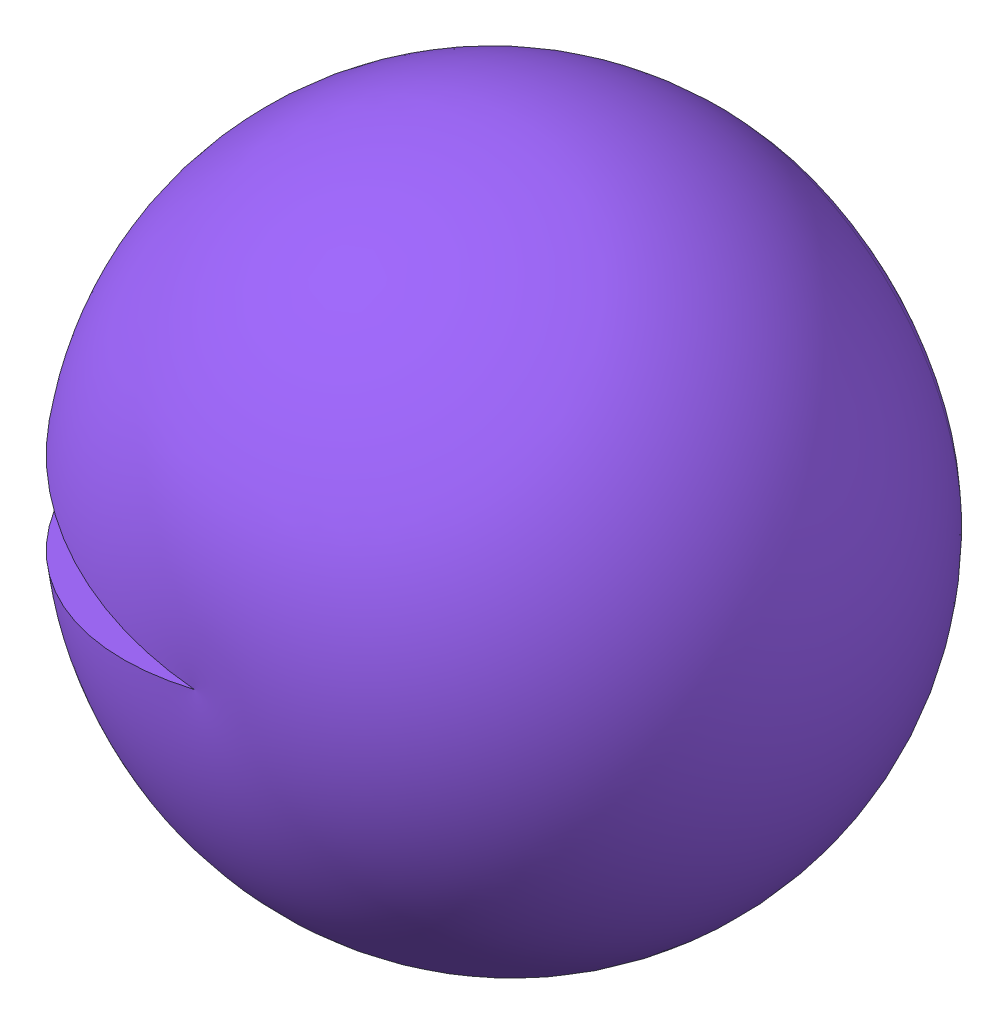
SolidWorks assembly ER10-700 机器人数模 V1.1（2016）, configuration 默认. Lengths in mm.
Overall size (1413.02 1423.84 1227.19).
8 component instances, 8 part files, 22 mates.
Components (placement in the parent):
- 底座^ER10-700 机器人数模 V1.1（2016）-1: 底座^ER10-700 机器人数模 V1.1（2016） [默认] at (0 0 4.5) size (331.2 257.54 212.5) (virtual)
- 转座^ER10-700 机器人数模 V1.1（2016）-1: 转座^ER10-700 机器人数模 V1.1（2016） [默认] at (-42.2594 -87.3208 27.8672) size (250.04 268.23 264.5) (virtual)
- 大臂^ER10-700 机器人数模 V1.1（2016）-1: 大臂^ER10-700 机器人数模 V1.1（2016） [默认] at (50 0 376) x (0 1 0) z (1 0 0.000058) size (240 474.02 163.79) (virtual)
- 电机座^ER10-700 机器人数模 V1.1（2016）-1: 电机座^ER10-700 机器人数模 V1.1（2016） [默认] at (49.9808 0 706) x (1 0 0) z (0 -1 0) size (190.27 156.39 131) (virtual)
- 手腕体^ER10-700 机器人数模 V1.1（2016）-1: 手腕体^ER10-700 机器人数模 V1.1（2016） [默认] at (-0.0192 0 4.5) size (281 133.47 135.61) (virtual)
- 手腕^ER10-700 机器人数模 V1.1（2016）-1: 手腕^ER10-700 机器人数模 V1.1（2016） [默认] at (-0.0192 0 4.5) size (128.92 79 88) (virtual)
- 法兰^ER10-700 机器人数模 V1.1（2016）-2: 法兰^ER10-700 机器人数模 V1.1（2016） [默认] at (-0.0192 0 1487.5) x (1 0 0) z (0 0 -1) size (41.7 70.2 70.2) (virtual)
- 运动范围^ER10-700 机器人数模 V1.1（2016）-1: 运动范围^ER10-700 机器人数模 V1.1（2016） [默认] x (1 0 0) z (0 -1 0) size (1413.02 1227.19 1423.84) (virtual)
Mates (geometry in assembly coordinates):
- 重合1: coordinate: point of 底座^ER10-700 机器人数模 V1.1（2016）-1; point of assembly
- 同心1: concentric aligned: cylinder of 转座^ER10-700 机器人数模 V1.1（2016）-1 through (0 0 191.5) axis (0 0 1) radius 100; cylinder of 底座^ER10-700 机器人数模 V1.1（2016）-1 through (0 0 193.5) axis (0 0 1) radius 107.5
- 距离1: distance = 1 mm anti-aligned: plane of 转座^ER10-700 机器人数模 V1.1（2016）-1 through (111 -125 204.5) normal (0 0 -1); plane of 底座^ER10-700 机器人数模 V1.1（2016）-1 through (0 0 203.5) normal (0 0 1)
- 同心2: concentric aligned: cylinder of 转座^ER10-700 机器人数模 V1.1（2016）-1 through (50 90 376) axis (0 -1 0) radius 77.5; cylinder of 大臂^ER10-700 机器人数模 V1.1（2016）-1 through (50 88.5 376) axis (0 -1 0) radius 70
- 距离2: distance = 0.5 mm anti-aligned: plane of 大臂^ER10-700 机器人数模 V1.1（2016）-1 through (50 73.5 376) normal (0 1 0); plane of 转座^ER10-700 机器人数模 V1.1（2016）-1 through (50 74 376) normal (0 -1 0)
- 同心3: concentric anti-aligned: cylinder of 大臂^ER10-700 机器人数模 V1.1（2016）-1 through (49.9808 -55.5 706) axis (0 -1 0) radius 58.0136; cylinder of 电机座^ER10-700 机器人数模 V1.1（2016）-1 through (49.9808 -213.5635 706) axis (0 1 0) radius 55
- 距离3: distance = 0.5 mm anti-aligned: plane of 电机座^ER10-700 机器人数模 V1.1（2016）-1 through (49.9808 -56 706) normal (0 -1 0); plane of 大臂^ER10-700 机器人数模 V1.1（2016）-1 through (49.9808 -56.5 706) normal (0 1 0)
- 同心4: concentric anti-aligned: cylinder of 电机座^ER10-700 机器人数模 V1.1（2016）-1 through (126.9808 0 746) axis (1 0 0) radius 50; cylinder of 手腕体^ER10-700 机器人数模 V1.1（2016）-1 through (146.9808 0 746) axis (-1 0 0) radius 49
- 距离4: distance = 0.5 mm anti-aligned: plane of 手腕体^ER10-700 机器人数模 V1.1（2016）-1 through (142.4808 0 746) normal (-1 0 0); plane of 电机座^ER10-700 机器人数模 V1.1（2016）-1 through (141.9808 0 746) normal (1 0 0)
- 同心5: concentric aligned: cylinder of 手腕体^ER10-700 机器人数模 V1.1（2016）-1 through (379.4808 -46 746) axis (0 1 0) radius 40.5; cylinder of 手腕^ER10-700 机器人数模 V1.1（2016）-1 through (379.4808 -30 746) axis (0 1 0) radius 40
- 距离5: distance = 0.5 mm anti-aligned: plane of 手腕^ER10-700 机器人数模 V1.1（2016）-1 through (379.4808 -33 746) normal (0 -1 0); plane of 手腕体^ER10-700 机器人数模 V1.1（2016）-1 through (379.4808 -33.5 746) normal (0 1 0)
- 同心7: concentric anti-aligned: cylinder of 手腕^ER10-700 机器人数模 V1.1（2016）-1 through (440.7808 0 746) axis (-1 0 0) radius 26.5; cylinder of 法兰^ER10-700 机器人数模 V1.1（2016）-2 through (425.9808 0 746) axis (1 0 0) radius 26.5
- 重合7: coincident anti-aligned: plane of 手腕^ER10-700 机器人数模 V1.1（2016）-1 through (439.9808 -100 646) normal (1 0 0); plane of 法兰^ER10-700 机器人数模 V1.1（2016）-2 through (439.9808 35.5212 710.4788) normal (-1 0 0)
- LimitAngle1: limit planar angle = 0 rad aligned: plane of 转座^ER10-700 机器人数模 V1.1（2016）-1 through (1.5 -111 207.5) normal (-1 0 0); plane of 底座^ER10-700 机器人数模 V1.1（2016）-1 through (1.5 -111 208.5) normal (-1 0 0)
- LimitAngle2: limit planar angle = 0.000058 rad aligned: plane of 转座^ER10-700 机器人数模 V1.1（2016）-1 through (131 -79 377.5) normal (0 0 -1); plane of 大臂^ER10-700 机器人数模 V1.1（2016）-1 through (137.9999 -68.5 377.5051) normal (0.000058 0 -1)
- LimitAngle4: limit planar angle = 0.000058 rad aligned: plane of 大臂^ER10-700 机器人数模 V1.1（2016）-1 through (48.4771 -60.5 769.4999) normal (1 0 0.000058); plane of 电机座^ER10-700 机器人数模 V1.1（2016）-1 through (48.4808 -51 765) normal (1 0 0)
- LimitAngle5: limit planar angle = 0 rad aligned: plane of 电机座^ER10-700 机器人数模 V1.1（2016）-1 through (136.9808 -61 747.5) normal (0 0 -1); plane of 手腕体^ER10-700 机器人数模 V1.1（2016）-1 through (142.4808 -61 747.5) normal (0 0 -1)
- LimitAngle6: limit planar angle = 0 rad aligned: plane of 手腕^ER10-700 机器人数模 V1.1（2016）-1 through (377.9808 34 830) normal (1 0 0); plane of 手腕体^ER10-700 机器人数模 V1.1（2016）-1 through (377.9808 34.5 829) normal (1 0 0)
- LimitAngle7: limit planar angle = 0 rad anti-aligned: plane of 手腕^ER10-700 机器人数模 V1.1（2016）-1 through (-0.0192 0 4.5) normal (0 1 0); plane of 法兰^ER10-700 机器人数模 V1.1（2016）-2 through (-0.0192 0 1487.5) normal (0 -1 0)
- 重合15: coincident: point of 底座^ER10-700 机器人数模 V1.1（2016）-1; point of 运动范围^ER10-700 机器人数模 V1.1（2016）-1
- 重合16: coincident anti-aligned: plane of 底座^ER10-700 机器人数模 V1.1（2016）-1 through (0 0 4.5) normal (0 1 0); plane of 运动范围^ER10-700 机器人数模 V1.1（2016）-1 through (0 0 0) normal (0 -1 0)
- 重合17: coincident anti-aligned: plane of 底座^ER10-700 机器人数模 V1.1（2016）-1 through (-80 -80 0) normal (0 0 -1); plane of 运动范围^ER10-700 机器人数模 V1.1（2016）-1 through (0 0 0) normal (0 0 1)
